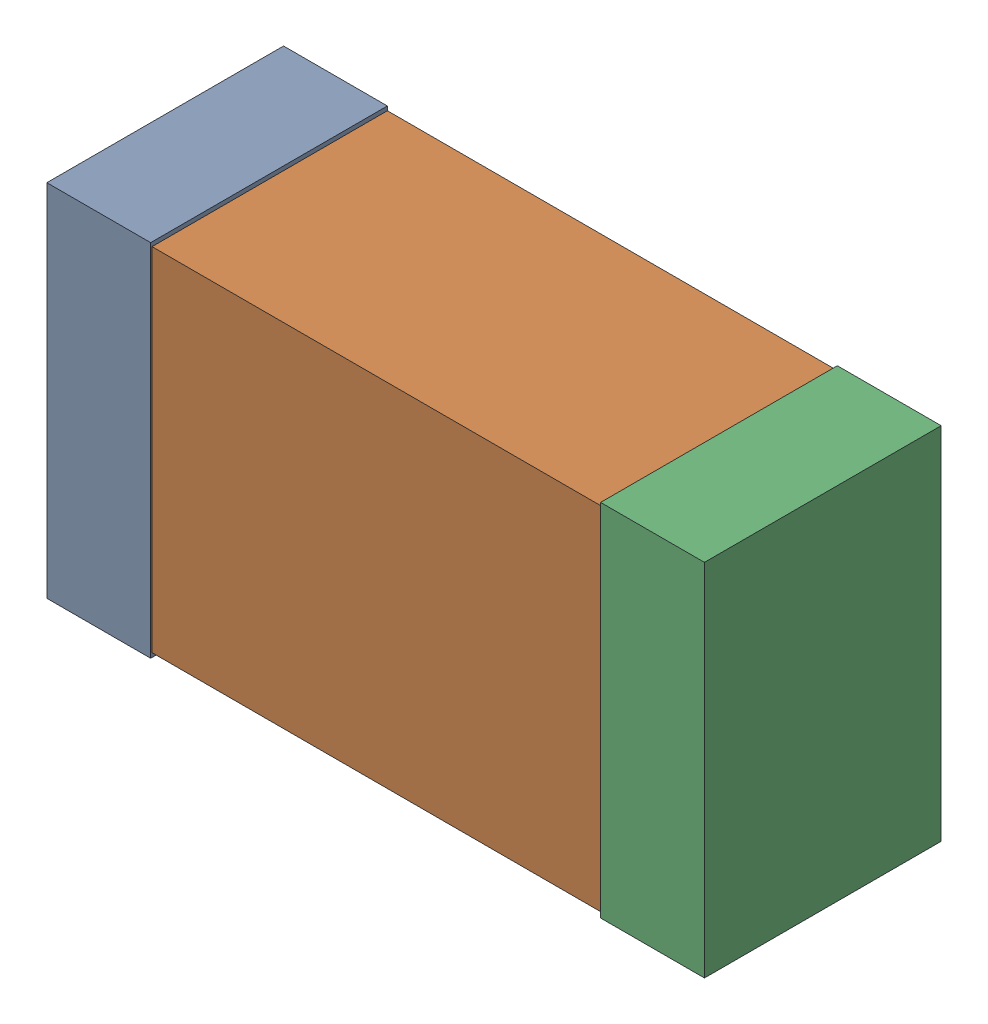
SolidWorks assembly C13_Motor_10Kanaloa_v2.0.0_Motor, configuration Default. Lengths in mm.
Overall size (2.38 1.3 0.85).
6 component instances, 2 part files, 0 mates.
Components (placement in the parent):
- 352877648-1: 352877648 [Default] at (102.378 170.434 0) size (0.38 1.3 0.85)
  - Extruded_14-1: Extruded_14 [Default] at origin size (0.38 1.3 0.85)
- 352877392-1: 352877392 [Default] at (103.378 170.434 0) size (2.2 1.27 0.85)
  - Extruded_15-1: Extruded_15 [Default] at origin size (2.2 1.27 0.85)
- 352877648-2: 352877648 [Default] at (104.378 170.434 0) size (0.38 1.3 0.85)
  - Extruded_14-1: Extruded_14 [Default] at origin size (0.38 1.3 0.85)
